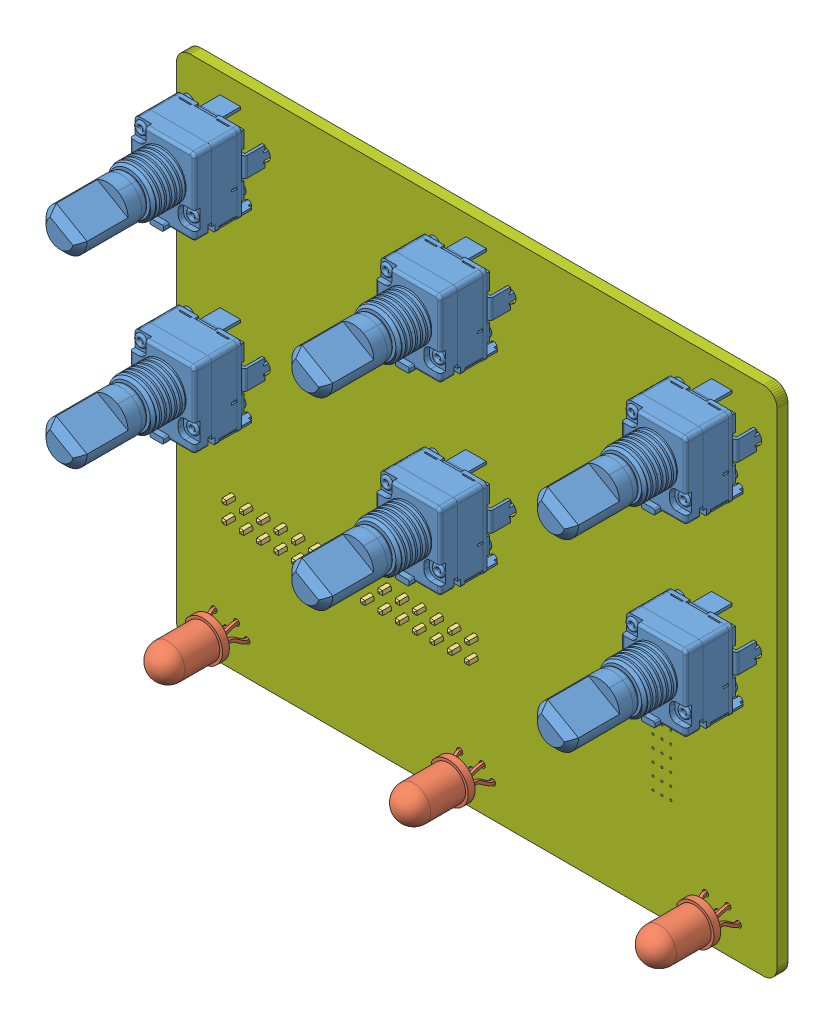
SolidWorks assembly teensy-dsp-frontend, configuration Default. Lengths in mm.
Overall size (88 75 35.83).
38 component instances, 7 part files, 0 mates.
Components (placement in the parent):
- teensy-dsp-frontend.step-1: teensy-dsp-frontend.step [Default] at origin size (88 75 35.83)
  - P0915N-FC15AR50K.step-1: P0915N-FC15AR50K.step [Default] at (60 -65.225 7.63) x (1 0 0) z (0 -1 0) size (12.1 28.7 12.5)
    - COMPOUND.step-1: COMPOUND.step [Default] at origin size (12.1 28.7 12.5)
  - P0915N-FC15AR50K.step-2: P0915N-FC15AR50K.step [Default] at (96 -65.225 7.63) x (1 0 0) z (0 -1 0) size (12.1 28.7 12.5)
    - COMPOUND.step-1: COMPOUND.step [Default] at origin size (12.1 28.7 12.5)
  - P0915N-FC15AR50K.step-3: P0915N-FC15AR50K.step [Default] at (132 -38.225 7.63) x (1 0 0) z (0 -1 0) size (12.1 28.7 12.5)
    - COMPOUND.step-1: COMPOUND.step [Default] at origin size (12.1 28.7 12.5)
  - P0915N-FC15AR50K.step-4: P0915N-FC15AR50K.step [Default] at (60 -38.225 7.63) x (1 0 0) z (0 -1 0) size (12.1 28.7 12.5)
    - COMPOUND.step-1: COMPOUND.step [Default] at origin size (12.1 28.7 12.5)
  - P0915N-FC15AR50K.step-5: P0915N-FC15AR50K.step [Default] at (96 -38.225 7.63) x (1 0 0) z (0 -1 0) size (12.1 28.7 12.5)
    - COMPOUND.step-1: COMPOUND.step [Default] at origin size (12.1 28.7 12.5)
  - LED_D5.0mm-4_RGB_Staggered_Pins.step-1: LED_D5.0mm-4_RGB_Staggered_Pins.step [Default] at (93.5 -99.725 1.63) size (5.51 5.8 15.6)
    - SOLID.step-1: SOLID.step [Default] at origin size (5.51 5.8 15.6)
  - LED_D5.0mm-4_RGB_Staggered_Pins.step-2: LED_D5.0mm-4_RGB_Staggered_Pins.step [Default] at (129.5 -99.725 1.63) size (5.51 5.8 15.6)
    - SOLID.step-1: SOLID.step [Default] at origin size (5.51 5.8 15.6)
  - LED_D5.0mm-4_RGB_Staggered_Pins.step-3: LED_D5.0mm-4_RGB_Staggered_Pins.step [Default] at (57.5 -99.725 1.63) size (5.51 5.8 15.6)
    - SOLID.step-1: SOLID.step [Default] at origin size (5.51 5.8 15.6)
  - P0915N-FC15AR50K.step-6: P0915N-FC15AR50K.step [Default] at (132 -65.225 7.63) x (1 0 0) z (0 -1 0) size (12.1 28.7 12.5)
    - COMPOUND.step-1: COMPOUND.step [Default] at origin size (12.1 28.7 12.5)
  - IDC-Header_2x15_P2.54mm_Vertical.step-1: IDC-Header_2x15_P2.54mm_Vertical.step [Default] at (60.1639 -84.1439 -0.05) x (0 -1 0) z (0 0 -1) size (9.1 45.76 12.1)
    - SOLID-0.step-1: SOLID-0.step [Default] at origin size (9.1 45.76 12.1)
  - R_1206_3216Metric.step-1: R_1206_3216Metric.step [Default] at (135.1739 -81.1439 -0.05) x (-1 0 0) z (0 0 -1) size (3.2 1.6 0.55)
    - SOLID-1.step-1: SOLID-1.step [Default] at origin size (3.2 1.6 0.55)
  - R_1206_3216Metric.step-2: R_1206_3216Metric.step [Default] at (135.1739 -91.3039 -0.05) x (-1 0 0) z (0 0 -1) size (3.2 1.6 0.55)
    - SOLID-1.step-1: SOLID-1.step [Default] at origin size (3.2 1.6 0.55)
  - R_1206_3216Metric.step-3: R_1206_3216Metric.step [Default] at (113.1739 -87.1439 -0.05) x (-1 0 0) z (0 0 -1) size (3.2 1.6 0.55)
    - SOLID-1.step-1: SOLID-1.step [Default] at origin size (3.2 1.6 0.55)
  - HTSSOP-28-1EP_4.4x9.7mm_P0.65mm_EP3.4x9.5mm.step-1: HTSSOP-28-1EP_4.4x9.7mm_P0.65mm_EP3.4x9.5mm.step [Default] at (123.1239 -86.0339 -0.05) x (-1 0 0) z (0 0 -1) size (6.4 9.7 1.2)
    - SOLID-2.step-1: SOLID-2.step [Default] at origin size (6.4 9.7 1.2)
  - C_1206_3216Metric.step-1: C_1206_3216Metric.step [Default] at (113.1614 -79.1439 -0.05) x (-1 0 0) z (0 0 -1) size (3.2 1.6 1.6)
    - SOLID-3.step-1: SOLID-3.step [Default] at origin size (3.2 1.6 1.6)
  - R_1206_3216Metric.step-4: R_1206_3216Metric.step [Default] at (113.1739 -83.1439 -0.05) x (-1 0 0) z (0 0 -1) size (3.2 1.6 0.55)
    - SOLID-1.step-1: SOLID-1.step [Default] at origin size (3.2 1.6 0.55)
  - R_1206_3216Metric.step-5: R_1206_3216Metric.step [Default] at (135.1739 -86.2239 -0.05) x (-1 0 0) z (0 0 -1) size (3.2 1.6 0.55)
    - SOLID-1.step-1: SOLID-1.step [Default] at origin size (3.2 1.6 0.55)
  - R_1206_3216Metric.step-6: R_1206_3216Metric.step [Default] at (113.1739 -91.1439 -0.05) x (-1 0 0) z (0 0 -1) size (3.2 1.6 0.55)
    - SOLID-1.step-1: SOLID-1.step [Default] at origin size (3.2 1.6 0.55)
  - PCB.step-1: PCB.step [Default] at origin size (88 75 1.58)
